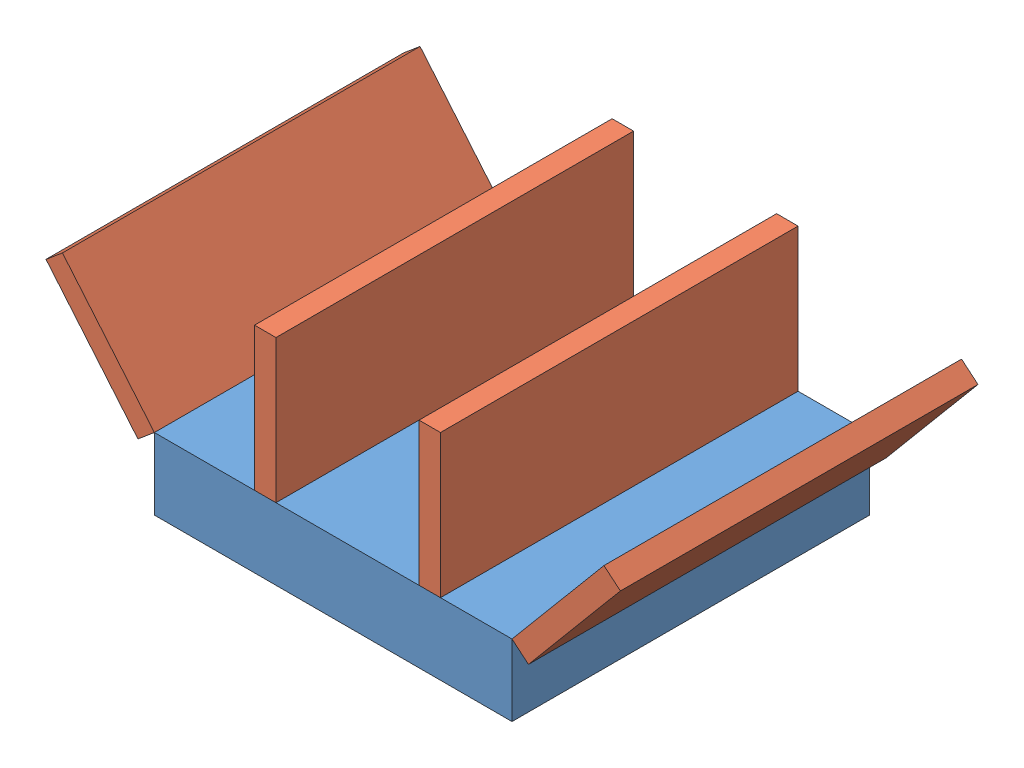
SolidWorks assembly Assem2, configuration Default. Lengths in mm.
Overall size (203.98 76.2 127).
5 component instances, 2 part files, 12 mates.
Components (placement in the parent):
- Base_2013-1: Base_2013 [Default] at (49.6602 60.3343 91.7019) size (127 25.4 127)
- Wing_2013-1: Wing_2013 [Default] at (-52.3306 119.7513 155.2019) x (0.642788 -0.766044 0) z (0 0 1) size (50.8 7.62 127)
- Wing_2013-2: Wing_2013 [Default] at (80.1402 136.5343 155.2019) x (0 -1 0) z (0 0 1) size (50.8 7.62 127)
- Wing_2013-3: Wing_2013 [Default] at (21.7202 136.5343 155.2019) x (0 -1 0) z (0 0 1) size (50.8 7.62 127)
- Wing_2013-4: Wing_2013 [Default] at (145.8138 124.6494 155.2019) x (-0.642788 -0.766044 0) z (0 0 1) size (50.8 7.62 127)
Mates (geometry in assembly coordinates):
- Coincident1: coincident aligned: line of Base_2013-1 through (113.1602 85.7343 155.2019) axis (0 0 -1); line of Wing_2013-4 through (113.1602 85.7343 155.2019) axis (0 0 -1)
- Coincident4: coincident: point of Base_2013-1; point of Wing_2013-4
- Angle2: planar angle = 2.268928 rad aligned: line of Wing_2013-4 through (145.8138 124.6494 155.2019) axis (-0.642788 -0.766044 0); line of Base_2013-1 through (-13.8398 85.7343 155.2019) axis (1 0 0)
- Coincident7: coincident anti-aligned: line of Base_2013-1 through (-13.8398 85.7343 28.2019) axis (0 0 1); line of Wing_2013-1 through (-13.8398 85.7343 155.2019) axis (0 0 -1)
- Coincident8: coincident: point of Base_2013-1; point of Wing_2013-1
- Angle5: planar angle = 2.268928 rad anti-aligned: plane of Wing_2013-1 through (-46.4934 124.6494 155.2019) normal (0.766044 0.642788 0); plane of Base_2013-1 through (49.6602 85.7343 91.7019) normal (0 1 0)
- Coincident12: coincident anti-aligned: plane of Base_2013-1 through (49.6602 85.7343 91.7019) normal (0 1 0); plane of Wing_2013-2 through (87.7602 85.7343 155.2019) normal (0 -1 0)
- Coincident13: coincident anti-aligned: line of Base_2013-1 through (-13.8398 85.7343 155.2019) axis (1 0 0); line of Wing_2013-2 through (87.7602 85.7343 155.2019) axis (-1 0 0)
- Distance2: distance = 25.4 mm: line of Wing_2013-4 through (113.1602 85.7343 155.2019) axis (0 0 -1); line of Wing_2013-2 through (87.7602 85.7343 155.2019) axis (0 0 -1)
- Coincident15: coincident: plane of Base_2013-1 through (49.6602 85.7343 91.7019) normal (0 1 0); plane of Wing_2013-3 through (29.3402 85.7343 155.2019) normal (0 -1 0)
- Coincident16: coincident: line of Base_2013-1 through (-13.8398 85.7343 155.2019) axis (1 0 0); line of Wing_2013-3 through (29.3402 85.7343 155.2019) axis (-1 0 0)
- Distance3: distance = 50.8 mm: line of Wing_2013-2 through (80.1402 136.5343 155.2019) axis (0 -1 0); line of Wing_2013-3 through (29.3402 136.5343 155.2019) axis (0 -1 0)
